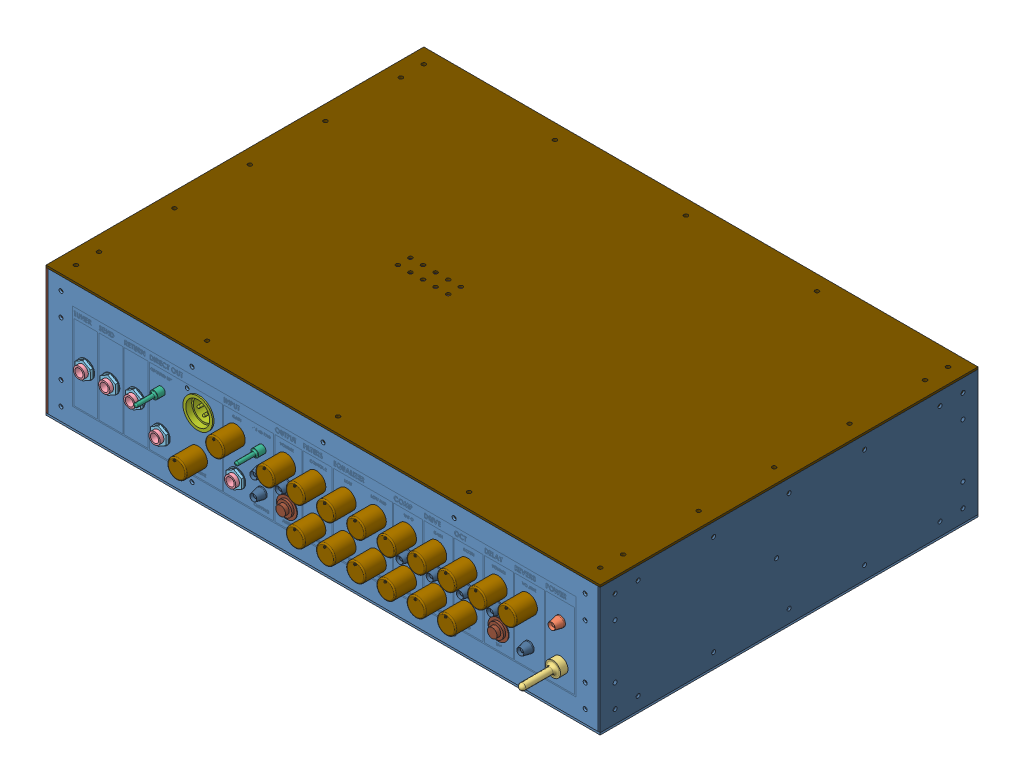
SolidWorks assembly case, configuration Défaut. Lengths in mm.
Overall size (440 103.17 334.66).
91 component instances, 30 part files, 80 mates.
Components (placement in the parent):
- bottom-1: bottom [Défaut] at (82.8434 -23.4462 400) size (440 20.64 300)
- transformer_600VA_50V-1: transformer_600VA_50V [Défaut] at (139.7036 53.1413 445.5869) x (0.007275 0 0.999974) z (0 -1 0) size (160 160 75)
- transformer_50VA_18V-1: transformer_50VA_18V [Défaut] at (-40.4956 17.1413 441.5143) x (0.811418 0 -0.584466) z (0 -1 0) size (100 100 39)
- pcb_psu-1: pcb_psu [Défaut] at (-42.8614 40.5988 471.3593) x (1 0 0) z (0 -1 0) size (100 100 53.6)
- diode_bridge-1: diode_bridge [Défaut] at (223.7824 16.3613 503.2397) x (0 1 0) z (-1 0 0) size (30 30 22)
- power_cap-1: power_cap [Défaut] at (119.74 -21.8587 601.6465) x (-1 0 0) z (0 1 0) size (160 90 60)
- pcb_amp-1: pcb_amp [Défaut] at (-149.9926 -10.2712 447.0225) x (0 0 -1) z (0 1 0) size (120 55 19.6)
- pcb_processing-1: pcb_processing [Défaut] at (-127.9926 -10.2712 592.2287) x (1 0 0) z (0 1 0) size (100 100 21.6)
- pcb_controller-1: pcb_controller [Défaut] at (-32.2176 -10.2712 592.2287) x (0 0 1) z (0 1 0) size (100 50 21.6)
- side_right-2: side_right [Défaut] at (223.7824 -3.0062 535.4208) x (0 0 -1) z (1 0 0) size (300 100 20.64)
- side_left-2: side_left [Défaut] at (-213.0426 -3.0062 475.6242) x (0 0 1) z (-1 0 0) size (300 100 20.64)
- side_back-1: side_back [Défaut] at (103.6807 -3.0062 357.11) x (-1 0 0) z (0 0 -1) size (436.83 100 1.59)
- iec_c14-1: iec_c14 [Défaut] at (54.8239 18.7625 357.11) x (-1 0 0) z (0 0 1) size (46.09 33 22.59)
- fan_80mm.step-1: fan_80mm.step [Défaut] at (-46.6536 28.1413 358.6975) x (1 0 0) z (0 -1 0) size (88.52 25.34 87.72)
- standoff_m3_10mm-1: standoff_m3_10mm [Défaut] at (-53.2176 -20.2712 546.2287) x (1 0 0) z (0 1 0) size (5.2 4.5 10)
- standoff_m3_10mm-2: standoff_m3_10mm [Défaut] at (-11.2176 -20.2712 638.2287) x (1 0 0) z (0 1 0) size (5.2 4.5 10)
- standoff_m3_10mm-3: standoff_m3_10mm [Défaut] at (-53.2176 -20.2712 638.2287) x (1 0 0) z (0 1 0) size (5.2 4.5 10)
- standoff_m3_10mm-4: standoff_m3_10mm [Défaut] at (-11.2176 -20.2712 546.2287) x (1 0 0) z (0 1 0) size (5.2 4.5 10)
- standoff_m3_10mm-5: standoff_m3_10mm [Défaut] at (-81.9926 -20.2712 638.2287) x (1 0 0) z (0 1 0) size (5.2 4.5 10)
- standoff_m3_10mm-6: standoff_m3_10mm [Défaut] at (-173.9926 -20.2712 546.2287) x (1 0 0) z (0 1 0) size (5.2 4.5 10)
- standoff_m3_10mm-7: standoff_m3_10mm [Défaut] at (-81.9926 -20.2712 546.2287) x (1 0 0) z (0 1 0) size (5.2 4.5 10)
- standoff_m3_10mm-8: standoff_m3_10mm [Défaut] at (-173.9926 -20.2712 638.2287) x (1 0 0) z (0 1 0) size (5.2 4.5 10)
- standoff_m3_10mm-9: standoff_m3_10mm [Défaut] at (-173.9926 -10.2712 503.5225) x (1 0 0) z (0 -1 0) size (5.2 4.5 10)
- standoff_m3_10mm-10: standoff_m3_10mm [Défaut] at (-173.9926 -10.2712 390.5225) x (1 0 0) z (0 -1 0) size (5.2 4.5 10)
- standoff_m3_10mm-11: standoff_m3_10mm [Défaut] at (-125.9926 -10.2712 390.5225) x (1 0 0) z (0 -1 0) size (5.2 4.5 10)
- standoff_m3_10mm-12: standoff_m3_10mm [Défaut] at (-125.9926 -10.2712 503.5225) x (1 0 0) z (0 -1 0) size (5.2 4.5 10)
- speakon-1: speakon [Défaut] at (-161.1061 26.9034 357.11) size (26 31 28.5)
- middle-1: middle [Défaut] at (9.2204 -21.8587 523.9399) x (1 0 0) z (0 1 0) size (140.64 295.19 100)
- top-1: top [Défaut] at (42.8434 76.5538 400) size (440 20.64 300)
- front-1: front [Défaut] at (36.5849 -6.5386 257.11) size (436.83 100 61)
  - side_front-1: side_front [Défaut] at (-129.5258 3.5323 396.825) size (436.83 100 1.59)
  - led_green-1: led_green [Défaut] at (157.1975 45.6799 398.4125) size (8 8 22)
  - toggle_sw_hd-1: toggle_sw_hd [Défaut] at (211.5043 0.9981 377.825) size (19 29 53)
  - jack-1: jack [Défaut] at (-107.6275 7.6799 395.825) x (-1 0 0) z (0 0 -1) size (16 16 34)
  - jack-2: jack [Défaut] at (-187.6275 22.6799 395.825) x (-1 0 0) z (0 0 -1) size (16 16 34)
  - jack-3: jack [Défaut] at (-167.6275 7.6799 395.825) x (-1 0 0) z (0 0 -1) size (16 16 34)
  - jack-4: jack [Défaut] at (-207.6275 22.6799 395.825) x (-1 0 0) z (0 0 -1) size (16 16 34)
  - jack-5: jack [Défaut] at (-227.6275 22.6799 395.825) x (-1 0 0) z (0 0 -1) size (16 16 34)
  - jack_nut-1: jack_nut [Défaut] at (-219.6275 30.6799 398.4125) size (14 14 2.5)
  - jack_nut-2: jack_nut [Défaut] at (-199.6275 30.6799 398.4125) size (14 14 2.5)
  - jack_nut-3: jack_nut [Défaut] at (-159.6275 15.6799 398.4125) size (14 14 2.5)
  - toggle_sw-1: toggle_sw [Défaut] at (-101.8207 22.7481 387.325) size (12 12.5 32)
  - jack_nut-4: jack_nut [Défaut] at (-179.6275 30.6799 398.4125) size (14 14 2.5)
  - xlr-1: xlr [Défaut] at (-132.811 53.3465 394.825) size (26 31 27)
  - pot-1: pot [Défaut] at (-129.6275 15.6799 389.325) size (17 17 25)
  - knob-1: knob [Défaut] at (-129.6275 15.6799 399.325) x (0.972364 0.233468 0) z (0 0 1) size (15 15 18)
  - pot-2: pot [Défaut] at (-99.6275 45.6799 389.325) size (17 17 25)
  - knob-2: knob [Défaut] at (-99.6275 45.6799 399.325) size (15 15 18)
  - jack_nut-5: jack_nut [Défaut] at (-99.6275 15.6799 398.4125) size (14 14 2.5)
  - toggle_sw-2: toggle_sw [Défaut] at (-21.8207 22.7481 387.325) size (12 12.5 32)
  - led_red-1: led_red [Défaut] at (-79.6275 15.6799 398.4125) size (8 8 22)
  - pot-3: pot [Défaut] at (-59.6275 45.6799 389.325) size (17 17 25)
  - knob-3: knob [Défaut] at (-59.6275 45.6799 399.325) size (15 15 18)
  - led_red-2: led_red [Défaut] at (-59.6275 30.6799 398.4125) size (8 8 22)
  - pot-4: pot [Défaut] at (-35.6275 45.6799 389.325) size (17 17 25)
  - pot-5: pot [Défaut] at (-35.6275 15.6799 389.325) size (17 17 25)
  - knob-4: knob [Défaut] at (-35.6275 15.6799 399.325) size (15 15 18)
  - knob-5: knob [Défaut] at (-35.6275 45.6799 399.325) size (15 15 18)
  - pot-6: pot [Défaut] at (-11.6275 45.6799 389.325) size (17 17 25)
  - pot-7: pot [Défaut] at (12.3725 45.6799 389.325) size (17 17 25)
  - pot-8: pot [Défaut] at (-11.6275 15.6799 389.325) size (17 17 25)
  - pot-9: pot [Défaut] at (12.3725 15.6799 389.325) size (17 17 25)
  - knob-6: knob [Défaut] at (12.3725 15.6799 399.325) size (15 15 18)
  - knob-7: knob [Défaut] at (-11.6275 15.6799 399.325) size (15 15 18)
  - knob-8: knob [Défaut] at (12.3725 45.6799 399.325) size (15 15 18)
  - knob-9: knob [Défaut] at (-11.6275 45.6799 399.325) size (15 15 18)
  - pot-10: pot [Défaut] at (36.3725 45.6799 389.325) size (17 17 25)
  - pot-11: pot [Défaut] at (36.3725 15.6799 389.325) size (17 17 25)
  - pot-12: pot [Défaut] at (60.3725 45.6799 389.325) size (17 17 25)
  - pot-13: pot [Défaut] at (60.3725 15.6799 389.325) size (17 17 25)
  - knob-10: knob [Défaut] at (60.3725 15.6799 399.325) size (15 15 18)
  - knob-11: knob [Défaut] at (60.3725 45.6799 399.325) size (15 15 18)
  - knob-12: knob [Défaut] at (36.3725 15.6799 399.325) size (15 15 18)
  - knob-13: knob [Défaut] at (36.3725 45.6799 399.325) size (15 15 18)
  - led_red-3: led_red [Défaut] at (36.3725 30.6799 398.4125) size (8 8 22)
  - led_red-4: led_red [Défaut] at (60.3725 30.6799 398.4125) size (8 8 22)
  - led_red-5: led_red [Défaut] at (84.3725 30.6799 398.4125) size (8 8 22)
  - led_red-6: led_red [Défaut] at (108.3725 30.6799 398.4125) size (8 8 22)
  - pot-14: pot [Défaut] at (84.3725 45.6799 389.325) size (17 17 25)
  - pot-15: pot [Défaut] at (84.3725 15.6799 389.325) size (17 17 25)
  - pot-16: pot [Défaut] at (108.3725 45.6799 389.325) size (17 17 25)
  - knob-14: knob [Défaut] at (84.3725 45.6799 399.325) size (15 15 18)
  - knob-15: knob [Défaut] at (84.3725 15.6799 399.325) size (15 15 18)
  - knob-16: knob [Défaut] at (108.3725 45.6799 399.325) size (15 15 18)
  - button-1: button [Défaut] at (108.3725 15.6799 398.4125) size (16.2 16.2 25.3)
  - button-2: button [Défaut] at (-59.6275 15.6799 398.4125) size (16.2 16.2 25.3)
  - pot-17: pot [Défaut] at (132.3725 45.6799 389.325) size (17 17 25)
  - knob-17: knob [Défaut] at (132.3725 45.6799 399.325) size (15 15 18)
  - led_red-7: led_red [Défaut] at (132.3725 15.6799 398.4125) size (8 8 22)
  - led_red-8: led_red [Défaut] at (-79.6275 30.6799 398.4125) size (8 8 22)
- dsub-9-1: dsub-9 [Défaut] at (-168.0408 53.1413 329.7189) size (30.81 12.55 16.87)
Mates (geometry in assembly coordinates):
- Coïncidente1: coincident: plane of bottom-1 through (82.8434 -21.8587 400) normal (0 1 0); plane of transformer_600VA_50V-1 through (139.7036 -21.8587 445.5869) normal (0 -1 0)
- Coïncidente2: coincident: plane of bottom-1 through (82.8434 -21.8587 400) normal (0 1 0); plane of power_cap-1 through (119.74 -21.8587 601.6465) normal (0 -1 0)
- Coïncidente4: coincident: plane of bottom-1 through (82.8434 -21.8587 400) normal (0 1 0); plane of transformer_50VA_18V-1 through (-40.4956 -21.8587 441.5143) normal (0 -1 0)
- Parallèle2: parallel: plane of bottom-1 through (82.8434 -21.8587 400) normal (0 1 0); plane of pcb_psu-1 through (-42.8614 38.9988 471.3593) normal (0 -1 0)
- Parallèle4: parallel: plane of bottom-1 through (222.1949 -2.8087 358.6975) normal (-1 0 0); plane of power_cap-1 through (195.0873 -6.8587 634.4143) normal (1 0 0)
- Parallèle5: parallel: plane of bottom-1 through (-211.4551 -2.8087 358.6975) normal (0 0 1); plane of pcb_psu-1 through (-92.8614 38.9988 421.3593) normal (0 0 -1)
- Parallèle6: parallel: plane of bottom-1 through (82.8434 -21.8587 400) normal (0 1 0); plane of pcb_amp-1 through (-149.9926 -10.2712 447.0225) normal (0 -1 0)
- Parallèle7: parallel: plane of bottom-1 through (-211.4551 -2.8087 358.6975) normal (0 0 1); plane of pcb_amp-1 through (-177.4926 -8.6712 387.0225) normal (0 0 -1)
- Parallèle9: parallel: plane of bottom-1 through (82.8434 -21.8587 400) normal (0 1 0); plane of diode_bridge-1 through (216.7824 43.1413 500.5225) normal (0 1 0)
- Parallèle10: parallel: plane of bottom-1 through (82.8434 -21.8587 400) normal (0 1 0); plane of pcb_controller-1 through (-32.2176 -10.2712 592.2287) normal (0 -1 0)
- Parallèle11: parallel: plane of bottom-1 through (82.8434 -21.8587 400) normal (0 1 0); plane of pcb_processing-1 through (-127.9926 -10.2712 592.2287) normal (0 -1 0)
- Parallèle12: parallel: plane of bottom-1 through (-213.0426 -20.2712 653.935) normal (0 0 1); plane of pcb_controller-1 through (-10.7267 6.3288 601.2853) normal (0 0 1)
- Coïncidente16: coincident: plane of bottom-1 through (223.7824 -20.2712 357.11) normal (1 0 0); plane of side_right-2 through (223.7824 -3.0062 535.4208) normal (-1 0 0)
- Coïncidente17: coincident: plane of bottom-1 through (82.8434 -21.8587 400) normal (0 1 0); plane of side_right-2 through (225.3699 -21.8587 655.5225) normal (0 -1 0)
- Coïncidente19: coincident: plane of bottom-1 through (-174.6301 -21.8587 655.5225) normal (0 0 1); plane of side_right-2 through (225.3699 78.1413 655.5225) normal (0 0 1)
- Coaxiale1: concentric: cylinder of diode_bridge-1 through (216.7824 28.1413 515.5225) axis (1 0 0) radius 2.5; cylinder of side_right-2 through (204.7314 28.1413 515.5225) axis (1 0 0) radius 1.5875
- Coïncidente20: coincident: plane of diode_bridge-1 through (223.7824 16.3613 503.2397) normal (1 0 0); plane of side_right-2 through (223.7824 -3.0062 535.4208) normal (-1 0 0)
- Coïncidente21: coincident: plane of bottom-1 through (223.7824 -20.2712 357.11) normal (1 0 0); plane of side_right-2 through (223.7824 -3.0062 535.4208) normal (-1 0 0)
- Coïncidente22: coincident: plane of bottom-1 through (-213.0426 -20.2712 357.11) normal (0 0 -1); plane of side_right-2 through (222.1949 59.0913 357.11) normal (0 0 -1)
- Coïncidente23: coincident: plane of bottom-1 through (82.8434 -21.8587 400) normal (0 1 0); plane of side_right-2 through (225.3699 -21.8587 655.5225) normal (0 -1 0)
- Coaxiale2: concentric: cylinder of diode_bridge-1 through (216.7824 28.1413 515.5225) axis (1 0 0) radius 2.5; cylinder of side_right-2 through (204.7314 28.1413 515.5225) axis (1 0 0) radius 1.5875
- Coïncidente24: coincident: plane of bottom-1 through (-213.0426 -20.2712 357.11) normal (-1 0 0); plane of side_left-2 through (-213.0426 -3.0062 475.6242) normal (1 0 0)
- Coïncidente25: coincident: plane of bottom-1 through (-213.0426 -20.2712 357.11) normal (0 0 -1); plane of side_left-2 through (-211.4551 59.0913 357.11) normal (0 0 -1)
- Coïncidente26: coincident: plane of bottom-1 through (82.8434 -21.8587 400) normal (0 1 0); plane of side_left-2 through (-214.6301 -21.8587 355.5225) normal (0 -1 0)
- Coïncidente27: coincident: plane of bottom-1 through (-213.0426 -20.2712 357.11) normal (0 0 -1); plane of side_back-1 through (103.6807 -3.0062 357.11) normal (0 0 1)
- Coïncidente28: coincident: plane of side_right-2 through (223.7824 -3.0062 535.4208) normal (-1 0 0); plane of side_back-1 through (223.7824 78.1413 355.5225) normal (1 0 0)
- Coïncidente29: coincident: plane of bottom-1 through (82.8434 -21.8587 400) normal (0 1 0); plane of side_back-1 through (223.7824 -21.8587 355.5225) normal (0 -1 0)
- Coïncidente30: coincident: plane of side_back-1 through (43.1433 12.6413 355.5215) normal (0 1 0); plane of iec_c14-1 through (71.6433 12.6413 355.5225) normal (0 -1 0)
- Coïncidente31: coincident: plane of side_back-1 through (43.1433 43.6413 355.5215) normal (1 0 0); plane of iec_c14-1 through (43.1433 43.6413 355.5225) normal (-1 0 0)
- Coïncidente32: coincident: plane of side_back-1 through (103.6807 -3.0062 357.11) normal (0 0 1); plane of iec_c14-1 through (54.8239 18.7625 357.11) normal (0 0 -1)
- Coïncidente33: coincident: plane of bottom-1 through (-211.4551 -2.8087 358.6975) normal (0 0 1); plane of fan_80mm.step-1 through (-46.6536 -14.5732 358.6975) normal (0 0 -1)
- Coaxiale3: concentric: cylinder of side_back-1 through (-10.9036 63.8913 355.5215) axis (0 0 1) radius 2; cylinder of fan_80mm.step-1 through (-10.9036 63.8913 257.8107) axis (0 0 -1) radius 2
- Coaxiale4: concentric: cylinder of side_back-1 through (-82.4036 -7.6087 355.5215) axis (0 0 1) radius 2; cylinder of fan_80mm.step-1 through (-82.4036 -7.6087 257.8107) axis (0 0 -1) radius 2
- Coïncidente34: coincident: plane of standoff_m3_10mm-1 through (-53.2176 -10.2712 546.2287) normal (0 1 0); plane of standoff_m3_10mm-2 through (-11.2176 -10.2712 638.2287) normal (0 1 0)
- Coïncidente35: coincident: plane of standoff_m3_10mm-1 through (-53.2176 -10.2712 546.2287) normal (0 1 0); plane of standoff_m3_10mm-3 through (-53.2176 -10.2712 638.2287) normal (0 1 0)
- Coïncidente36: coincident: plane of standoff_m3_10mm-1 through (-53.2176 -10.2712 546.2287) normal (0 1 0); plane of standoff_m3_10mm-4 through (-11.2176 -10.2712 546.2287) normal (0 1 0)
- Coïncidente37: coincident: plane of pcb_controller-1 through (-32.2176 -10.2712 592.2287) normal (0 -1 0); plane of standoff_m3_10mm-1 through (-53.2176 -10.2712 546.2287) normal (0 1 0)
- Coaxiale5: concentric: cylinder of pcb_controller-1 through (-11.2176 -8.6712 638.2287) axis (0 -1 0) radius 1.6; cylinder of standoff_m3_10mm-2 through (-11.2176 -10.2712 638.2287) axis (0 -1 0) radius 1.5
- Coaxiale6: concentric: cylinder of pcb_controller-1 through (-53.2176 -8.6712 638.2287) axis (0 -1 0) radius 1.6; cylinder of standoff_m3_10mm-3 through (-53.2176 -10.2712 638.2287) axis (0 -1 0) radius 1.5
- Coaxiale7: concentric: cylinder of pcb_controller-1 through (-11.2176 -8.6712 546.2287) axis (0 -1 0) radius 1.6; cylinder of standoff_m3_10mm-4 through (-11.2176 -10.2712 546.2287) axis (0 -1 0) radius 1.5
- Coaxiale8: concentric: cylinder of pcb_controller-1 through (-53.2176 -8.6712 546.2287) axis (0 -1 0) radius 1.6; cylinder of standoff_m3_10mm-1 through (-53.2176 -10.2712 546.2287) axis (0 -1 0) radius 1.5
- Coïncidente38: coincident: plane of bottom-1 through (82.8434 -20.2712 400) normal (0 1 0); plane of standoff_m3_10mm-3 through (-53.2176 -20.2712 638.2287) normal (0 -1 0)
- Coaxiale11: concentric: cylinder of bottom-1 through (-11.2176 -23.4472 638.2287) axis (0 1 0) radius 1.5875; cylinder of standoff_m3_10mm-2 through (-11.2176 -10.2712 638.2287) axis (0 -1 0) radius 1.5
- Coaxiale12: concentric: cylinder of bottom-1 through (-53.2176 -23.4472 638.2287) axis (0 1 0) radius 1.5875; cylinder of standoff_m3_10mm-3 through (-53.2176 -10.2712 638.2287) axis (0 -1 0) radius 1.5
- Coïncidente39: coincident: plane of standoff_m3_10mm-5 through (-81.9926 -10.2712 638.2287) normal (0 1 0); plane of standoff_m3_10mm-6 through (-173.9926 -10.2712 546.2287) normal (0 1 0)
- Coïncidente40: coincident: plane of standoff_m3_10mm-5 through (-81.9926 -10.2712 638.2287) normal (0 1 0); plane of standoff_m3_10mm-7 through (-81.9926 -10.2712 546.2287) normal (0 1 0)
- Coïncidente41: coincident: plane of standoff_m3_10mm-5 through (-81.9926 -10.2712 638.2287) normal (0 1 0); plane of standoff_m3_10mm-8 through (-173.9926 -10.2712 638.2287) normal (0 1 0)
- Coïncidente42: coincident: plane of pcb_processing-1 through (-127.9926 -10.2712 592.2287) normal (0 -1 0); plane of standoff_m3_10mm-5 through (-81.9926 -10.2712 638.2287) normal (0 1 0)
- Coaxiale13: concentric: cylinder of pcb_processing-1 through (-81.9926 -8.6712 638.2287) axis (0 -1 0) radius 1.6; cylinder of standoff_m3_10mm-5 through (-81.9926 -10.2712 638.2287) axis (0 -1 0) radius 1.5
- Coaxiale14: concentric: cylinder of pcb_processing-1 through (-81.9926 -8.6712 546.2287) axis (0 -1 0) radius 1.6; cylinder of standoff_m3_10mm-7 through (-81.9926 -10.2712 546.2287) axis (0 -1 0) radius 1.5
- Coaxiale15: concentric: cylinder of pcb_processing-1 through (-173.9926 -8.6712 546.2287) axis (0 -1 0) radius 1.6; cylinder of standoff_m3_10mm-6 through (-173.9926 -10.2712 546.2287) axis (0 -1 0) radius 1.5
- Coaxiale16: concentric: cylinder of pcb_processing-1 through (-173.9926 -8.6712 638.2287) axis (0 -1 0) radius 1.6; cylinder of standoff_m3_10mm-8 through (-173.9926 -10.2712 638.2287) axis (0 -1 0) radius 1.5
- Coïncidente43: coincident: plane of bottom-1 through (82.8434 -20.2712 400) normal (0 1 0); plane of standoff_m3_10mm-8 through (-173.9926 -20.2712 638.2287) normal (0 -1 0)
- Coaxiale17: concentric: cylinder of bottom-1 through (-81.9926 -23.4472 638.2287) axis (0 1 0) radius 1.5875; cylinder of standoff_m3_10mm-5 through (-81.9926 -10.2712 638.2287) axis (0 -1 0) radius 1.5
- Coaxiale18: concentric: cylinder of bottom-1 through (-173.9926 -23.4472 638.2287) axis (0 1 0) radius 1.5875; cylinder of standoff_m3_10mm-8 through (-173.9926 -10.2712 638.2287) axis (0 -1 0) radius 1.5
- Coïncidente44: coincident: plane of standoff_m3_10mm-11 through (-125.9926 -10.2712 390.5225) normal (0 1 0); plane of standoff_m3_10mm-12 through (-125.9926 -10.2712 503.5225) normal (0 1 0)
- Coïncidente45: coincident: plane of standoff_m3_10mm-10 through (-173.9926 -10.2712 390.5225) normal (0 1 0); plane of standoff_m3_10mm-11 through (-125.9926 -10.2712 390.5225) normal (0 1 0)
- Coïncidente46: coincident: plane of standoff_m3_10mm-9 through (-173.9926 -10.2712 503.5225) normal (0 1 0); plane of standoff_m3_10mm-10 through (-173.9926 -10.2712 390.5225) normal (0 1 0)
- Coïncidente47: coincident: plane of pcb_amp-1 through (-149.9926 -10.2712 447.0225) normal (0 -1 0); plane of standoff_m3_10mm-12 through (-125.9926 -10.2712 503.5225) normal (0 1 0)
- Coaxiale19: concentric: cylinder of pcb_amp-1 through (-125.9926 -8.6712 503.5225) axis (0 -1 0) radius 1.6; cylinder of standoff_m3_10mm-12 through (-125.9926 -20.2712 503.5225) axis (0 1 0) radius 1.5
- Coaxiale20: concentric: cylinder of pcb_amp-1 through (-173.9926 -8.6712 503.5225) axis (0 -1 0) radius 1.6; cylinder of standoff_m3_10mm-9 through (-173.9926 -20.2712 503.5225) axis (0 1 0) radius 1.5
- Coaxiale21: concentric: cylinder of pcb_amp-1 through (-173.9926 -8.6712 390.5225) axis (0 -1 0) radius 1.6; cylinder of standoff_m3_10mm-10 through (-173.9926 -20.2712 390.5225) axis (0 1 0) radius 1.5
- Coaxiale22: concentric: cylinder of pcb_amp-1 through (-125.9926 -8.6712 390.5225) axis (0 -1 0) radius 1.6; cylinder of standoff_m3_10mm-11 through (-125.9926 -20.2712 390.5225) axis (0 1 0) radius 1.5
- Coïncidente48: coincident: plane of bottom-1 through (82.8434 -20.2712 400) normal (0 1 0); plane of standoff_m3_10mm-12 through (-125.9926 -20.2712 503.5225) normal (0 -1 0)
- Coaxiale23: concentric: cylinder of bottom-1 through (-125.9926 -23.4472 503.5225) axis (0 1 0) radius 1.5875; cylinder of standoff_m3_10mm-12 through (-125.9926 -20.2712 503.5225) axis (0 1 0) radius 1.5
- Coaxiale24: concentric: cylinder of bottom-1 through (-173.9926 -23.4472 390.5225) axis (0 1 0) radius 1.5875; cylinder of standoff_m3_10mm-10 through (-173.9926 -20.2712 390.5225) axis (0 1 0) radius 1.5
- Coïncidente49: coincident: plane of side_back-1 through (103.6807 -3.0062 357.11) normal (0 0 1); plane of speakon-1 through (-161.1061 26.9034 357.11) normal (0 0 -1)
- Coaxiale25: concentric: cylinder of side_back-1 through (-177.5426 11.1413 355.5215) axis (0 0 1) radius 1.5312; cylinder of speakon-1 through (-177.5426 11.1413 361.61) axis (0 0 -1) radius 1.2353
- Coaxiale26: concentric: cylinder of side_back-1 through (-158.5426 35.1413 355.5215) axis (0 0 1) radius 1.5312; cylinder of speakon-1 through (-158.5426 35.1413 361.61) axis (0 0 -1) radius 1.1375
- Coïncidente50: coincident: plane of bottom-1 through (82.8434 -21.8587 400) normal (0 1 0); plane of middle-1 through (9.2204 -21.8587 523.9399) normal (0 -1 0)
- Coïncidente52: coincident: plane of bottom-1 through (-104.6301 -20.2712 530.5225) normal (1 0 0); plane of middle-1 through (-104.6301 78.1413 357.105) normal (-1 0 0)
- Coïncidente53: coincident: plane of side_left-2 through (-213.0426 -3.0062 475.6242) normal (1 0 0); plane of top-1 through (-213.0426 78.1413 357.11) normal (-1 0 0)
- Coïncidente55: coincident: plane of middle-1 through (9.2204 78.1413 523.9399) normal (0 1 0); plane of top-1 through (42.8434 78.1413 400) normal (0 -1 0)
- Coïncidente56: coincident: plane of top-1 through (-213.0426 78.1413 653.935) normal (0 0 1); plane of front-1/side_front-1 through (-92.9409 -3.0062 653.935) normal (0 0 -1)
- Coïncidente57: coincident: plane of bottom-1 through (82.8434 -21.8587 400) normal (0 1 0); plane of front-1/side_front-1 through (-213.0426 -21.8587 655.5225) normal (0 -1 0)
- Coïncidente58: coincident: plane of side_left-2 through (-213.0426 -3.0062 475.6242) normal (1 0 0); plane of front-1/side_front-1 through (-213.0426 78.1413 655.5225) normal (-1 0 0)
- Coïncidente59: coincident: plane of side_back-1 through (103.6807 -3.0062 357.11) normal (0 0 1); plane of dsub-9-1 through (-168.0408 53.1413 357.11) normal (0 0 -1)
- Coaxiale29: concentric: cylinder of side_back-1 through (-180.5376 53.1413 355.5215) axis (0 0 1) radius 1.5875; cylinder of dsub-9-1 through (-180.5376 53.1413 358.38) axis (0 0 1) radius 1.524
- Parallèle13: parallel: cylinder of side_back-1 through (-155.5476 53.1413 355.5215) axis (0 0 1) radius 1.5875; cylinder of dsub-9-1 through (-155.544 53.1413 358.38) axis (0 0 1) radius 1.524
- Coïncidente60: coincident: plane of side_back-1 through (103.6807 -3.0062 357.11) normal (0 0 1); plane of top-1 through (-213.0426 78.1413 357.11) normal (0 0 -1)
